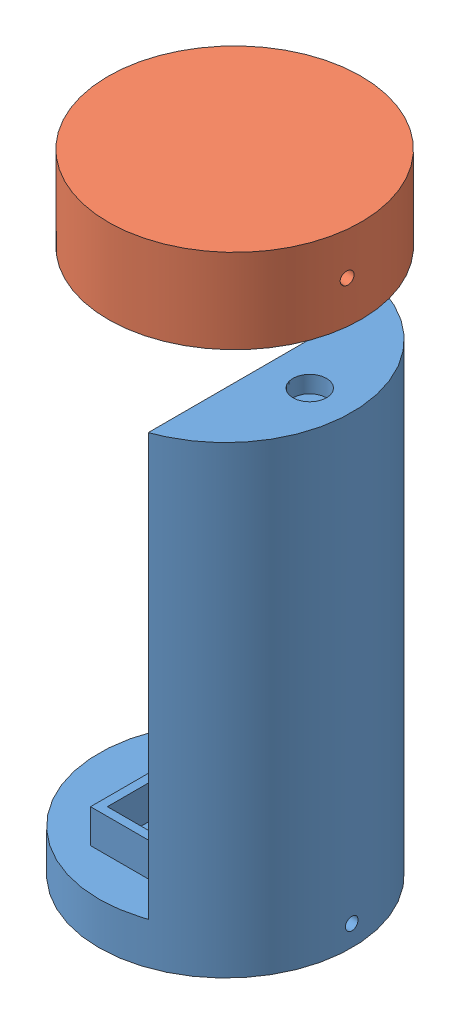
SolidWorks assembly Prototype 1 assembly, configuration Default. Lengths in mm.
Overall size (83.71 188.09 83.71).
2 component instances, 2 part files, 1 mates.
Components (placement in the parent):
- Prototype 1-1: Prototype 1 [Default] at (91.345 26.4343 118.1173) size (76.2 139.7 76.2)
- prototype 1b-1: prototype 1b [Default] at (91.4826 214.5291 115.4778) x (0.994586 0 0.103916) z (0.103916 0 -0.994586) size (76.2 30.48 76.2)
Mates (geometry in assembly coordinates):
- Concentric1: concentric: cylinder of Prototype 1-1 through (116.745 161.0543 118.1173) axis (0 1 0) radius 5.08; cylinder of prototype 1b-1 through (116.745 184.0491 118.1173) axis (0 1 0) radius 5.08
